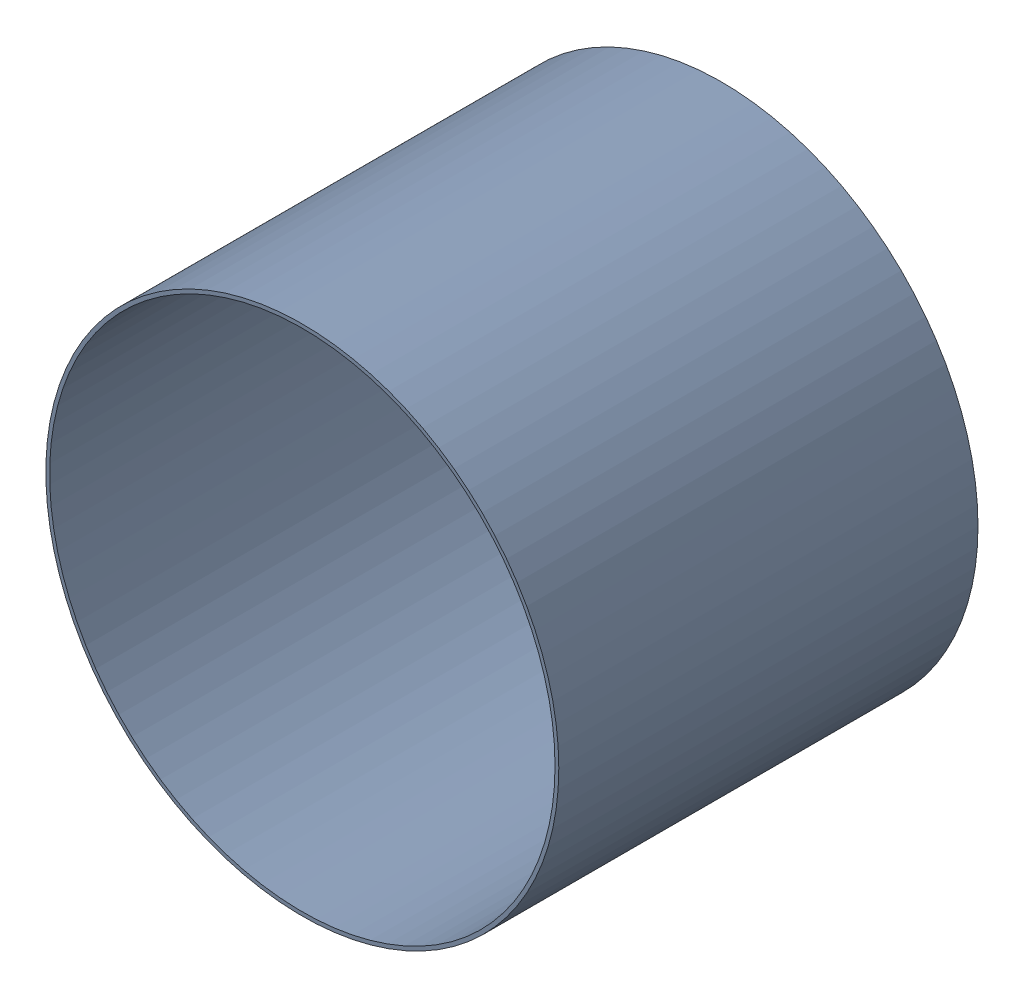
SolidWorks assembly Pad Free-3(60mm,64mm) on Multi-Layer-1, configuration По умолчанию. Lengths in mm.
Overall size (3.45 3.45 2.82).
2 component instances, 1 part files, 0 mates.
Components (placement in the parent):
- Pad Hole-1-1: Pad Hole-1 [По умолчанию] at (60 64 -2.8302) size (3.45 3.45 2.82)
  - Pad Hole-Part-1-1-1: Pad Hole-Part-1-1 [По умолчанию] at origin size (3.45 3.45 2.82)
